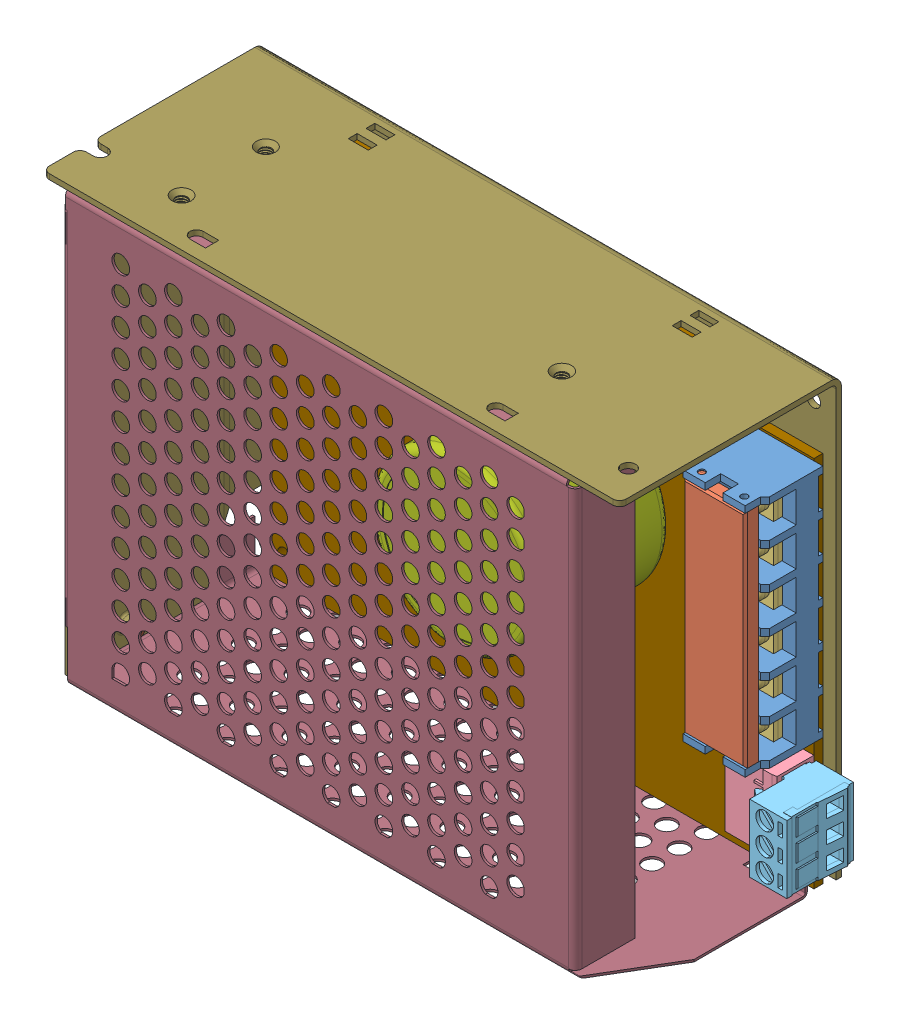
SolidWorks assembly Spindle Power supply, configuration Default. Lengths in mm.
Overall size (140.88 98 50.05).
20 component instances, 13 part files, 0 mates.
Components (placement in the parent):
- Spindle Power supply.step-1: Spindle Power supply.step [Default] at origin size (140.88 98 50.05)
  - Terminal block v1.step-1: Terminal block v1.step [Default] at (133.5 32.7893 7.7) x (0 1 0) z (0 0 1) size (53 15 16.5)
    - Component11.step-1: Component11.step [Default] at origin size (53 15 16.5)
    - Component12.step-1: Component12.step [Default] at origin size (53 14 3)
    - Terminal point.step-1: Terminal point.step [Default] at origin size (6.8 6.8 7.5)
    - Terminal point.step-2: Terminal point.step [Default] at (8.6 0 0) size (6.8 6.8 7.5)
    - Terminal point.step-3: Terminal point.step [Default] at (17.2 0 0) size (6.8 6.8 7.5)
    - Terminal point.step-4: Terminal point.step [Default] at (25.8 0 0) size (6.8 6.8 7.5)
    - Terminal point.step-5: Terminal point.step [Default] at (34.4 0 0) size (6.8 6.8 7.5)
    - Terminal point.step-6: Terminal point.step [Default] at (43 0 0) size (6.8 6.8 7.5)
  - 3P Plugin male v1.step-1: 3P Plugin male v1.step [Default] at (131.5 -18.18 7.7) x (0 1 0) z (0 0 1) size (16.84 12 12.5)
  - 3P Plugin female v1.step-1: 3P Plugin female v1.step [Default] at (132 -18.18 7.7) x (0 1 0) z (0 0 1) size (15.24 18.03 15)
  - Standoff.step-1: Standoff.step [Default] at origin size (6.93 6 5.79)
  - Capacitor.step-1: Capacitor.step [Default] at origin size (38 38 30)
  - Screw.step-1: Screw.step [Default] at origin size (7 7 7.06)
  - PCB.step-1: PCB.step [Default] at origin size (122.5 93 2)
  - Standoff (1).step-1: Standoff (1).step [Default] at origin size (6 6.93 5.8)
  - Screw (1).step-1: Screw (1).step [Default] at origin size (7.05 7 7)
  - Aluminum case.step-1: Aluminum case.step [Default] at origin size (130 98 50)
  - Cover.step-1: Cover.step [Default] at origin size (126 96.8 48.8)
